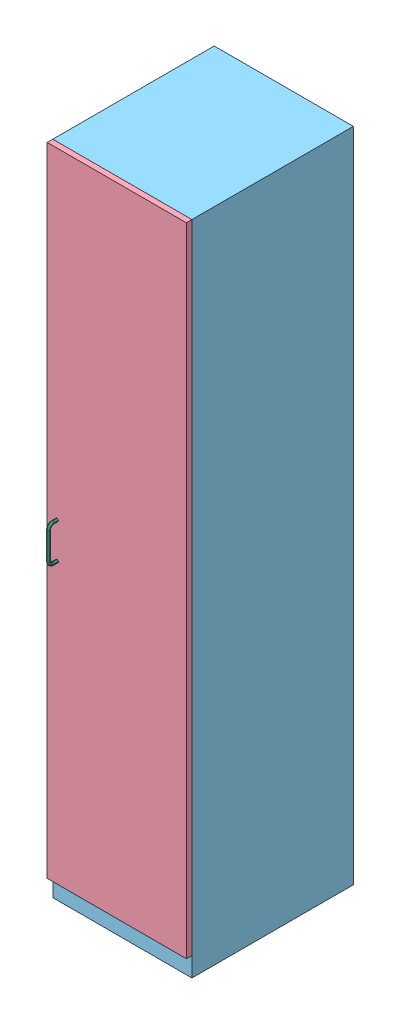
SolidWorks assembly PAX-R, configuration Standard. Lengths in mm.
Overall size (500 2360 635).
8 component instances, 7 part files, 24 mates.
Components (placement in the parent):
- KOMPLIMENT-Schublade-1: KOMPLIMENT-Schublade [Standard] at (250 250 295) size (480 160 570)
- KOMPLEMENT-Regalbode-2: KOMPLEMENT-Regalbode [Standard] at (250 610 295) size (480 10 570)
- KOMPLEMENT-Netzdrahtkorb-1: KOMPLEMENT-Netzdrahtkorb [Standard] at (250 230 295) size (480 160 570)
- KOMPLIMENT-Schublade-2: KOMPLIMENT-Schublade [Standard] at (250 430 295) size (480 160 570)
- BALLSTAD-Tür-229-1: BALLSTAD-Tür-229 [Standard] at (250 1215 580) size (500 2290 20)
- Pax-Korpus-Kleiderschrank-236-1: Pax-Korpus-Kleiderschrank-236 [Standard] at (250 0 290) size (500 2360 580)
- ATTEST-1: ATTEST [Standard] at (40 1139 600) x (0 -1 0) z (-1 0 0) size (138 35 10)
- KOMPLEMENT-Hosen-1: KOMPLEMENT-Hosen [Standard] at (250 1220 20) size (480 30 560)
Mates (geometry in assembly coordinates):
- Abstand3: distance = 20 mm anti-aligned: plane of KOMPLIMENT-Schublade-2 through (250 590 295) normal (0 1 0); plane of KOMPLEMENT-Regalbode-2 through (250 610 295) normal (0 -1 0)
- Abstand7: distance = 20 mm anti-aligned: plane of KOMPLEMENT-Netzdrahtkorb-1 through (250 230 295) normal (0 1 0); plane of KOMPLIMENT-Schublade-1 through (250 250 295) normal (0 -1 0)
- Deckungsgleich1: coincident anti-aligned: plane of Pax-Korpus-Kleiderschrank-236-1 through (250 0 290) normal (0 -1 0); plane of assembly
- Deckungsgleich2: coincident anti-aligned: plane of Pax-Korpus-Kleiderschrank-236-1 through (0 10 580) normal (-1 0 0); plane of assembly
- Deckungsgleich3: coincident anti-aligned: plane of Pax-Korpus-Kleiderschrank-236-1 through (0 10 0) normal (0 0 -1); plane of assembly
- Deckungsgleich4: coincident aligned: plane of BALLSTAD-Tür-229-1 through (0 2360 600) normal (0 1 0); plane of Pax-Korpus-Kleiderschrank-236-1 through (250 2360 290) normal (0 1 0)
- Deckungsgleich5: coincident aligned: plane of BALLSTAD-Tür-229-1 through (0 70 600) normal (-1 0 0); plane of Pax-Korpus-Kleiderschrank-236-1 through (0 10 580) normal (-1 0 0)
- Deckungsgleich6: coincident anti-aligned: plane of BALLSTAD-Tür-229-1 through (250 1215 580) normal (0 0 -1); plane of Pax-Korpus-Kleiderschrank-236-1 through (0 10 580) normal (0 0 1)
- Deckungsgleich7: coincident anti-aligned: plane of BALLSTAD-Tür-229-1 through (250 1215 600) normal (0 0 1); plane of ATTEST-1 through (30 1208 600) normal (0 0 -1)
- Abstand8: distance = 30 mm: line of ATTEST-1 through (30 1090 630) axis (0 1 0); plane of BALLSTAD-Tür-229-1 through (0 70 600) normal (-1 0 0)
- Abstand9: distance = 1000 mm: line of ATTEST-1 through (35 1070 615) axis (0 0 -1); plane of BALLSTAD-Tür-229-1 through (0 70 600) normal (0 -1 0)
- Deckungsgleich10: coincident anti-aligned: plane of KOMPLEMENT-Netzdrahtkorb-1 through (250 70 295) normal (0 -1 0); plane of Pax-Korpus-Kleiderschrank-236-1 through (250 70 290) normal (0 1 0)
- Deckungsgleich11: coincident: line of KOMPLEMENT-Netzdrahtkorb-1 through (10 230 10) axis (0 0 1); plane of Pax-Korpus-Kleiderschrank-236-1 through (10 2350 580) normal (1 0 0)
- Deckungsgleich12: coincident: line of KOMPLEMENT-Netzdrahtkorb-1 through (490 230 10) axis (-1 0 0); plane of Pax-Korpus-Kleiderschrank-236-1 through (10 2350 10) normal (0 0 1)
- Abstand10: distance = 20 mm anti-aligned: plane of KOMPLIMENT-Schublade-2 through (250 430 295) normal (0 -1 0); plane of KOMPLIMENT-Schublade-1 through (250 410 295) normal (0 1 0)
- Deckungsgleich14: coincident anti-aligned: plane of KOMPLIMENT-Schublade-1 through (10 260 10) normal (0 0 -1); plane of Pax-Korpus-Kleiderschrank-236-1 through (10 2350 10) normal (0 0 1)
- Deckungsgleich15: coincident anti-aligned: plane of KOMPLIMENT-Schublade-1 through (10 260 580) normal (-1 0 0); plane of Pax-Korpus-Kleiderschrank-236-1 through (10 2350 580) normal (1 0 0)
- Deckungsgleich16: coincident anti-aligned: plane of KOMPLIMENT-Schublade-2 through (10 440 10) normal (0 0 -1); plane of Pax-Korpus-Kleiderschrank-236-1 through (10 2350 10) normal (0 0 1)
- Deckungsgleich17: coincident anti-aligned: plane of KOMPLIMENT-Schublade-2 through (490 440 580) normal (1 0 0); plane of Pax-Korpus-Kleiderschrank-236-1 through (490 2350 10) normal (-1 0 0)
- Deckungsgleich18: coincident anti-aligned: plane of KOMPLEMENT-Regalbode-2 through (10 620 10) normal (0 0 -1); plane of Pax-Korpus-Kleiderschrank-236-1 through (10 2350 10) normal (0 0 1)
- Deckungsgleich19: coincident anti-aligned: plane of KOMPLEMENT-Regalbode-2 through (490 620 580) normal (1 0 0); plane of Pax-Korpus-Kleiderschrank-236-1 through (490 2350 10) normal (-1 0 0)
- Deckungsgleich20: coincident anti-aligned: plane of Pax-Korpus-Kleiderschrank-236-1 through (10 2350 10) normal (0 0 1); plane of KOMPLEMENT-Hosen-1 through (490 1250 10) normal (0 0 -1)
- Deckungsgleich21: coincident anti-aligned: plane of Pax-Korpus-Kleiderschrank-236-1 through (490 2350 10) normal (-1 0 0); plane of KOMPLEMENT-Hosen-1 through (490 1250 570) normal (1 0 0)
- Abstand11: distance = 600 mm anti-aligned: plane of KOMPLEMENT-Hosen-1 through (250 1220 20) normal (0 -1 0); plane of KOMPLEMENT-Regalbode-2 through (250 620 295) normal (0 1 0)
